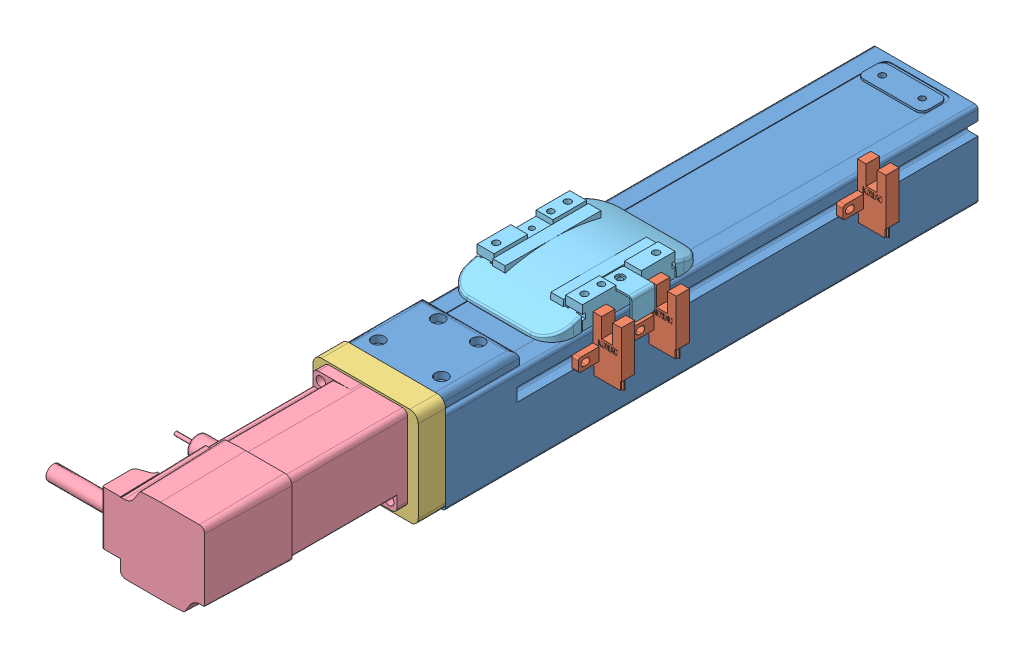
SolidWorks assembly S5M-BC-100W, configuration 默认. Lengths in mm.
Overall size (97.2 54 362.5).
7 component instances, 5 part files, 20 mates.
Components (placement in the parent):
- S5-BC导轨^S5M-BC-100W-1: S5-BC导轨^S5M-BC-100W [默认] x (-1 0 0) z (0 0 -1) size (50 48 253) (virtual)
-  传感器^S5M-BC-100W-1:  传感器^S5M-BC-100W [默认] at (31.75 37.6 -44) x (1 0 0) z (0 0 -1) size (13.5 27.2 26.1) (virtual)
-  传感器^S5M-BC-100W-2:  传感器^S5M-BC-100W [默认] at (31.75 37.6 -70.1) x (1 0 0) z (0 0 -1) size (13.5 27.2 26.1) (virtual)
-  传感器^S5M-BC-100W-3:  传感器^S5M-BC-100W [默认] at (31.75 37.6 -169.7) x (1 0 0) z (0 0 -1) size (13.5 27.2 26.1) (virtual)
- S5-BC-006-M10电机座^S5M-BC-100W-1: S5-BC-006-M10电机座^S5M-BC-100W [默认] at (0 26.9958 26) size (50 46.5 13) (virtual)
- 100W 电机^S5M-BC-100W-1: 100W 电机^S5M-BC-100W [默认] at (0 26.9958 95) x (0 -1 0) z (0 0 1) size (42.54 79.97 121.5) (virtual)
- S5-BC-滑块组件^S5M-BC-100W-1: S5-BC-滑块组件^S5M-BC-100W [Default] at (16.8713 13.2727 -107) size (57.33 40 73.16) (virtual)
Mates (geometry in assembly coordinates):
- 重合203: coincident: plane of S5-BC-006-M10电机座^S5M-BC-100W-1 through (-21.5 4.9958 39) normal (0 0 1); plane of 100W 电机^S5M-BC-100W-1 through (-0.0086 27.0155 39) normal (0 0 -1)
- 同心353: concentric: cylinder of S5-BC-006-M10电机座^S5M-BC-100W-1 through (0 26.9958 26) axis (0 0 1) radius 15.5; cylinder of 100W 电机^S5M-BC-100W-1 through (0 26.9958 39) axis (0 0 -1) radius 4
- 角度1: planar angle = 1.570796 rad: plane of 100W 电机^S5M-BC-100W-1 through (-17.5 6.9958 95) normal (0 -1 0); plane of S5-BC-006-M10电机座^S5M-BC-100W-1 through (25 43.9958 39) normal (1 0 0)
- 平行1: parallel: plane of S5-BC导轨^S5M-BC-100W-1 through (0 48 0) normal (0 1 0); plane of S5-BC-006-M10电机座^S5M-BC-100W-1 through (-21 47.9958 39) normal (0 1 0)
- 重合206: coincident: plane of S5-BC导轨^S5M-BC-100W-1 through (23.5 3 26) normal (0 0 1); plane of S5-BC-006-M10电机座^S5M-BC-100W-1 through (-21.5 4.9958 26) normal (0 0 -1)
- 同心356: concentric: cylinder of S5-BC导轨^S5M-BC-100W-1 through (17 37 26) axis (0 0 1) radius 1.25; cylinder of S5-BC-006-M10电机座^S5M-BC-100W-1 through (17 37 30) axis (0 0 -1) radius 3
- 重合214: coincident: plane of  传感器^S5M-BC-100W-2 through (38.5 48.7 -76.4) normal (1 0 0); plane of  传感器^S5M-BC-100W-3 through (38.5 48.7 -176) normal (1 0 0)
- 重合215: coincident: plane of  传感器^S5M-BC-100W-1 through (38.5 48.7 -50.3) normal (1 0 0); plane of  传感器^S5M-BC-100W-2 through (38.5 48.7 -76.4) normal (1 0 0)
- 重合216: coincident: plane of  传感器^S5M-BC-100W-1 through (25 26.5 -50.3) normal (0 -1 0); plane of  传感器^S5M-BC-100W-2 through (25 26.5 -76.4) normal (0 -1 0)
- 重合217: coincident: plane of  传感器^S5M-BC-100W-2 through (25 26.5 -76.4) normal (0 -1 0); plane of  传感器^S5M-BC-100W-3 through (25 26.5 -176) normal (0 -1 0)
- 重合218: coincident: plane of S5-BC导轨^S5M-BC-100W-1 through (25 42 -8) normal (1 0 0); plane of  传感器^S5M-BC-100W-3 through (25 48.7 -176) normal (-1 0 0)
- 距离8: distance = 25 mm: plane of  传感器^S5M-BC-100W-3 through (25 26.5 -176) normal (0 -1 0); plane of S5-BC导轨^S5M-BC-100W-1 through (-12 1.5 -8) normal (0 -1 0)
- 距离9: distance = 51 mm: plane of  传感器^S5M-BC-100W-3 through (38.5 26.5 -176) normal (0 0 -1); plane of S5-BC导轨^S5M-BC-100W-1 through (0 0 -227) normal (0 0 -1)
- 重合221: coincident: plane of  传感器^S5M-BC-100W-1 through (28 29.7 -60.2) normal (0 0 -1); plane of  传感器^S5M-BC-100W-2 through (28 29.7 -60.2) normal (0 0 1)
- 距离10: distance = 70 mm: plane of  传感器^S5M-BC-100W-1 through (38.5 26.5 -44) normal (0 0 1); plane of S5-BC导轨^S5M-BC-100W-1 through (23.5 3 26) normal (0 0 1)
- 距离11: distance = 54 mm: plane of S5-BC导轨^S5M-BC-100W-1 through (12 0 -219.5) normal (0 -1 0); plane of S5-BC-滑块组件^S5M-BC-100W-1 through (21 54 -75) normal (0 1 0)
- 重合224: coincident: plane of S5-BC导轨^S5M-BC-100W-1 through (0 0 0) normal (-1 0 0); plane of assembly through (0 0 0) normal (1 0 0)
- 重合225: coincident: plane of S5-BC导轨^S5M-BC-100W-1; plane of assembly through (0 0 0) normal (0 1 0)
- 重合226: coincident: plane of S5-BC导轨^S5M-BC-100W-1 through (0 0 0) normal (0 0 -1); plane of assembly through (0 0 0) normal (0 0 1)
- 宽度1: width: plane of S5-BC导轨^S5M-BC-100W-1 through (-25 42 -8) normal (-1 0 0); plane of S5-BC导轨^S5M-BC-100W-1 through (25 42 -8) normal (1 0 0); plane of S5-BC-滑块组件^S5M-BC-100W-1 through (25 48.5 -61) normal (1 0 0); plane of S5-BC-滑块组件^S5M-BC-100W-1 through (-25 48.5 -61) normal (-1 0 0)
